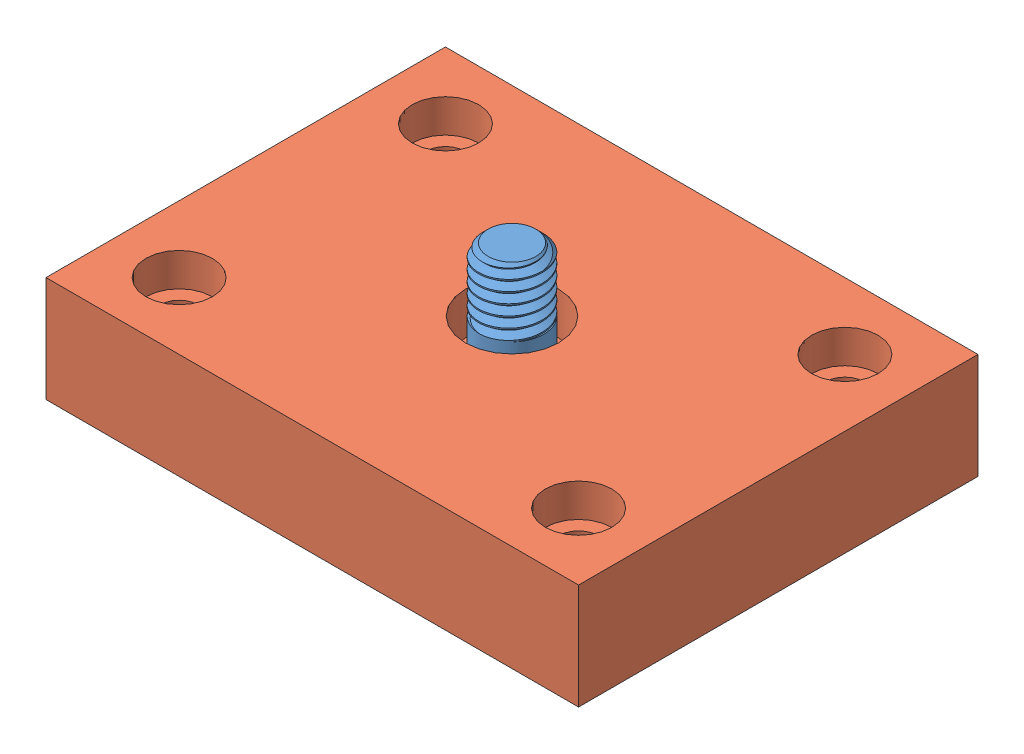
SolidWorks assembly Simple_Mount, configuration Default. Lengths in mm.
Overall size (80 26.26 60).
2 component instances, 2 part files, 6 mates.
Components (placement in the parent):
- 94358A310_COARSE-THREAD TO FINE-THREAD ADAPTING STUD-1: 94358A310_COARSE-THREAD TO FINE-THREAD ADAPTING STUD [94358A310] at (0 9.525 0) x (-1 0 0) z (0 1 0) size (10.06 10.07 26.26)
- Simple_Mount_Plate-1: Simple_Mount_Plate [Default] at origin size (80 15.88 60)
Mates (geometry in assembly coordinates):
- Coincident1: coincident aligned: plane of Simple_Mount_Plate-1 through (0 0 0) normal (0 1 0); plane of assembly through (0 0 0) normal (0 1 0)
- Coincident2: coincident aligned: plane of Simple_Mount_Plate-1 through (0 0 0) normal (0 0 1); plane of assembly through (0 0 0) normal (0 0 1)
- Coincident3: coincident aligned: plane of Simple_Mount_Plate-1 through (0 0 0) normal (1 0 0); plane of assembly through (0 0 0) normal (1 0 0)
- Coincident4: coincident aligned: plane of 94358A310_COARSE-THREAD TO FINE-THREAD ADAPTING STUD-1 through (0 -15.875 -4.7625) normal (0 -1 0); plane of Simple_Mount_Plate-1 through (0 -15.875 0) normal (0 -1 0)
- Coincident5: coincident aligned: plane of 94358A310_COARSE-THREAD TO FINE-THREAD ADAPTING STUD-1 through (0 9.525 0) normal (0 0 1); plane of assembly through (0 0 0) normal (0 0 1)
- Coincident6: coincident anti-aligned: plane of 94358A310_COARSE-THREAD TO FINE-THREAD ADAPTING STUD-1 through (0 9.525 0) normal (-1 0 0); plane of assembly through (0 0 0) normal (1 0 0)
